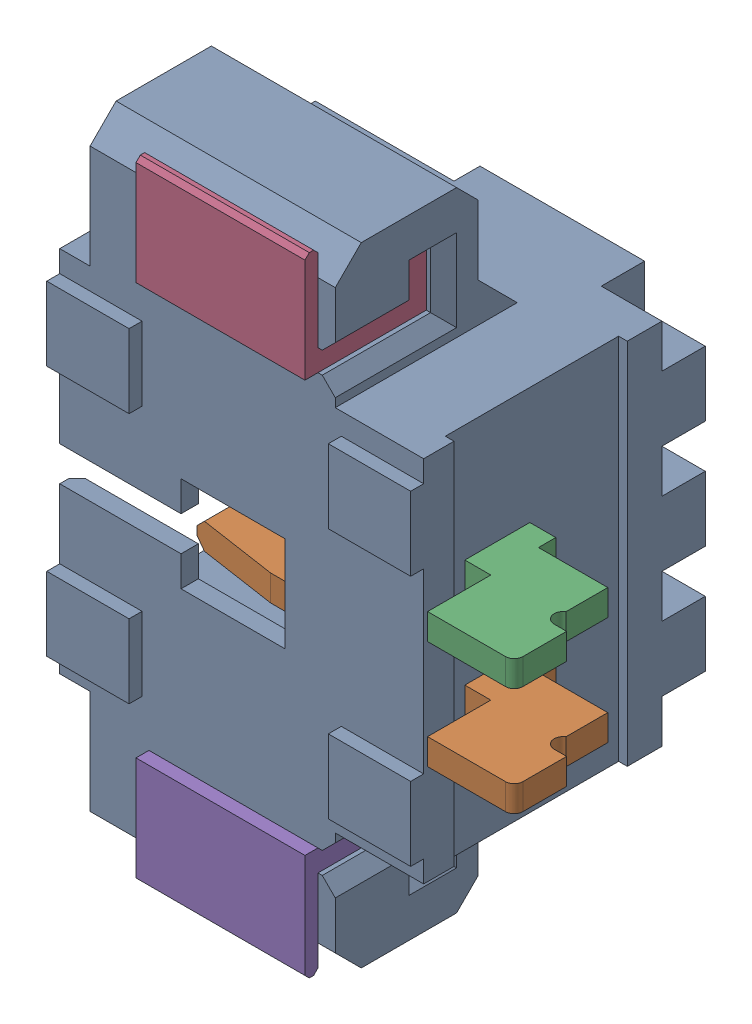
SolidWorks assembly J5, configuration Default. Lengths in mm.
Overall size (5.4 7.25 3.41).
6 component instances, 3 part files, 0 mates.
Components (placement in the parent):
- 653102131822-1: 653102131822 [Default] at (-1.6762 9.8799 -2.1415) x (0 1 0) z (0 0 -1) size (7.25 5.4 3.41)
  - 653102131822-1: 653102131822 [Default] at origin size (7.25 4.2 3.4)
  - 6531xx131822_PIN-1: 6531xx131822_PIN [Default] at (-0.625 2.7 -0.425) x (1 0 0) z (0 -1 0) size (0.3 1.48 4.54)
  - 6531xx131822_PIN-2: 6531xx131822_PIN [Default] at (0.625 2.7 -0.425) x (1 0 0) z (0 -1 0) size (0.3 1.48 4.54)
  - 6531xx131822_PIN_FLANGE-1: 6531xx131822_PIN_FLANGE [Default] at (2.5 -0.095 -1.05) size (1.25 1.95 1.4)
  - 6531xx131822_PIN_FLANGE-2: 6531xx131822_PIN_FLANGE [Default] at (-2.5 -0.095 -1.05) x (-1 0 0) z (0 0 1) size (1.25 1.95 1.4)
